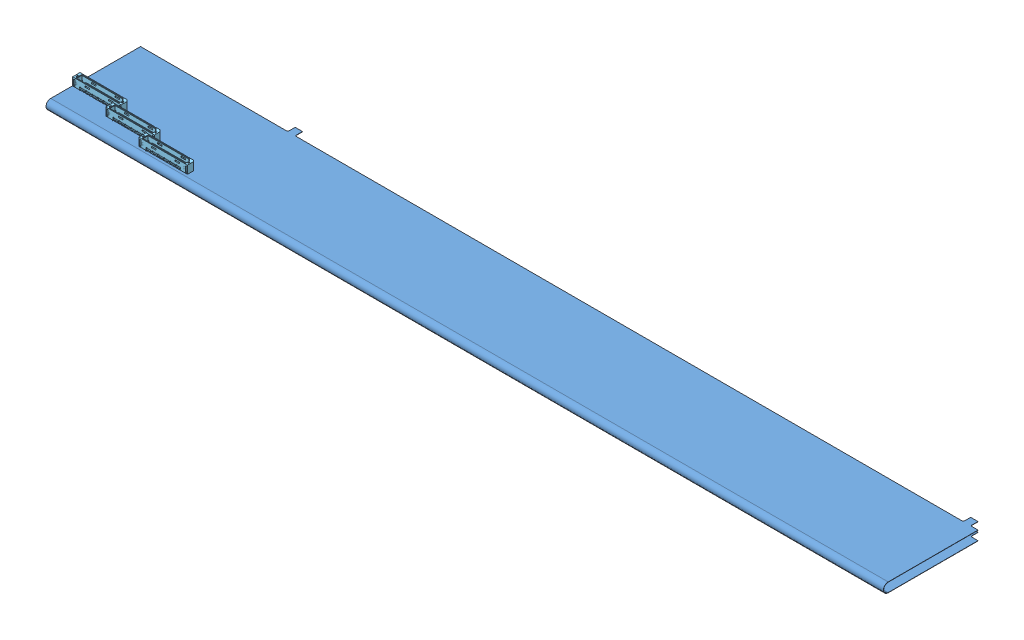
SolidWorks assembly IST Module rev 8_12 extruded, configuration Default. Lengths in mm.
Overall size (568.8 12.6 69.21).
53 component instances, 5 part files, 20 mates.
Components (placement in the parent):
- IST Kapton Hybrid rev 5_12 Extruded-1: IST Kapton Hybrid rev 5_12 Extruded [Default] at origin size (568.8 6.43 69.21)
- IST Silicon Sensor and APV assy rev 5_11-6: IST Silicon Sensor and APV assy rev 5_11 [Default] at (-38.65 -6.4251 21) x (1 0 0) z (0 0 -1) size (76.9 0.3 49.22)
  - IST Silicon Sensor rev1-2: IST Silicon Sensor rev1 [Default] x (-1 0 0) z (0 0 -1) size (76.9 0.3 40)
  - IST APV 25 Chip rev1-37: IST APV 25 Chip rev1 [Default] at (31.375 0 -25.119) x (0 0 1) z (-1 0 0) size (8.2 0.3 7.17)
  - IST APV 25 Chip rev1-2: IST APV 25 Chip rev1 [Default] at (18.825 0 -25.119) x (0 0 1) z (-1 0 0) size (8.2 0.3 7.17)
  - IST APV 25 Chip rev1-3: IST APV 25 Chip rev1 [Default] at (6.275 0 -25.119) x (0 0 1) z (-1 0 0) size (8.2 0.3 7.17)
  - IST APV 25 Chip rev1-4: IST APV 25 Chip rev1 [Default] at (-6.275 0 -25.119) x (0 0 1) z (-1 0 0) size (8.2 0.3 7.17)
  - IST APV 25 Chip rev1-5: IST APV 25 Chip rev1 [Default] at (-18.825 0 -25.119) x (0 0 1) z (-1 0 0) size (8.2 0.3 7.17)
  - IST APV 25 Chip rev1-6: IST APV 25 Chip rev1 [Default] at (-31.375 0 -25.119) x (0 0 1) z (-1 0 0) size (8.2 0.3 7.17)
- IST Silicon Sensor and APV assy rev 5_11-2: IST Silicon Sensor and APV assy rev 5_11 [Default] at (-115.95 -6.4251 21) x (1 0 0) z (0 0 -1) size (76.9 0.3 49.22)
  - IST Silicon Sensor rev1-2: IST Silicon Sensor rev1 [Default] x (-1 0 0) z (0 0 -1) size (76.9 0.3 40)
  - IST APV 25 Chip rev1-37: IST APV 25 Chip rev1 [Default] at (31.375 0 -25.119) x (0 0 1) z (-1 0 0) size (8.2 0.3 7.17)
  - IST APV 25 Chip rev1-2: IST APV 25 Chip rev1 [Default] at (18.825 0 -25.119) x (0 0 1) z (-1 0 0) size (8.2 0.3 7.17)
  - IST APV 25 Chip rev1-3: IST APV 25 Chip rev1 [Default] at (6.275 0 -25.119) x (0 0 1) z (-1 0 0) size (8.2 0.3 7.17)
  - IST APV 25 Chip rev1-4: IST APV 25 Chip rev1 [Default] at (-6.275 0 -25.119) x (0 0 1) z (-1 0 0) size (8.2 0.3 7.17)
  - IST APV 25 Chip rev1-5: IST APV 25 Chip rev1 [Default] at (-18.825 0 -25.119) x (0 0 1) z (-1 0 0) size (8.2 0.3 7.17)
  - IST APV 25 Chip rev1-6: IST APV 25 Chip rev1 [Default] at (-31.375 0 -25.119) x (0 0 1) z (-1 0 0) size (8.2 0.3 7.17)
- IST Silicon Sensor and APV assy rev 5_11-3: IST Silicon Sensor and APV assy rev 5_11 [Default] at (-193.25 -6.4251 21) x (1 0 0) z (0 0 -1) size (76.9 0.3 49.22)
  - IST Silicon Sensor rev1-2: IST Silicon Sensor rev1 [Default] x (-1 0 0) z (0 0 -1) size (76.9 0.3 40)
  - IST APV 25 Chip rev1-37: IST APV 25 Chip rev1 [Default] at (31.375 0 -25.119) x (0 0 1) z (-1 0 0) size (8.2 0.3 7.17)
  - IST APV 25 Chip rev1-2: IST APV 25 Chip rev1 [Default] at (18.825 0 -25.119) x (0 0 1) z (-1 0 0) size (8.2 0.3 7.17)
  - IST APV 25 Chip rev1-3: IST APV 25 Chip rev1 [Default] at (6.275 0 -25.119) x (0 0 1) z (-1 0 0) size (8.2 0.3 7.17)
  - IST APV 25 Chip rev1-4: IST APV 25 Chip rev1 [Default] at (-6.275 0 -25.119) x (0 0 1) z (-1 0 0) size (8.2 0.3 7.17)
  - IST APV 25 Chip rev1-5: IST APV 25 Chip rev1 [Default] at (-18.825 0 -25.119) x (0 0 1) z (-1 0 0) size (8.2 0.3 7.17)
  - IST APV 25 Chip rev1-6: IST APV 25 Chip rev1 [Default] at (-31.375 0 -25.119) x (0 0 1) z (-1 0 0) size (8.2 0.3 7.17)
- IST Silicon Sensor and APV assy rev 5_11-4: IST Silicon Sensor and APV assy rev 5_11 [Default] at (-270.55 -6.4251 21) x (1 0 0) z (0 0 -1) size (76.9 0.3 49.22)
  - IST Silicon Sensor rev1-2: IST Silicon Sensor rev1 [Default] x (-1 0 0) z (0 0 -1) size (76.9 0.3 40)
  - IST APV 25 Chip rev1-37: IST APV 25 Chip rev1 [Default] at (31.375 0 -25.119) x (0 0 1) z (-1 0 0) size (8.2 0.3 7.17)
  - IST APV 25 Chip rev1-2: IST APV 25 Chip rev1 [Default] at (18.825 0 -25.119) x (0 0 1) z (-1 0 0) size (8.2 0.3 7.17)
  - IST APV 25 Chip rev1-3: IST APV 25 Chip rev1 [Default] at (6.275 0 -25.119) x (0 0 1) z (-1 0 0) size (8.2 0.3 7.17)
  - IST APV 25 Chip rev1-4: IST APV 25 Chip rev1 [Default] at (-6.275 0 -25.119) x (0 0 1) z (-1 0 0) size (8.2 0.3 7.17)
  - IST APV 25 Chip rev1-5: IST APV 25 Chip rev1 [Default] at (-18.825 0 -25.119) x (0 0 1) z (-1 0 0) size (8.2 0.3 7.17)
  - IST APV 25 Chip rev1-6: IST APV 25 Chip rev1 [Default] at (-31.375 0 -25.119) x (0 0 1) z (-1 0 0) size (8.2 0.3 7.17)
- IST Silicon Sensor and APV assy rev 5_11-5: IST Silicon Sensor and APV assy rev 5_11 [Default] at (-347.85 -6.4251 21) x (1 0 0) z (0 0 -1) size (76.9 0.3 49.22)
  - IST Silicon Sensor rev1-2: IST Silicon Sensor rev1 [Default] x (-1 0 0) z (0 0 -1) size (76.9 0.3 40)
  - IST APV 25 Chip rev1-37: IST APV 25 Chip rev1 [Default] at (31.375 0 -25.119) x (0 0 1) z (-1 0 0) size (8.2 0.3 7.17)
  - IST APV 25 Chip rev1-2: IST APV 25 Chip rev1 [Default] at (18.825 0 -25.119) x (0 0 1) z (-1 0 0) size (8.2 0.3 7.17)
  - IST APV 25 Chip rev1-3: IST APV 25 Chip rev1 [Default] at (6.275 0 -25.119) x (0 0 1) z (-1 0 0) size (8.2 0.3 7.17)
  - IST APV 25 Chip rev1-4: IST APV 25 Chip rev1 [Default] at (-6.275 0 -25.119) x (0 0 1) z (-1 0 0) size (8.2 0.3 7.17)
  - IST APV 25 Chip rev1-5: IST APV 25 Chip rev1 [Default] at (-18.825 0 -25.119) x (0 0 1) z (-1 0 0) size (8.2 0.3 7.17)
  - IST APV 25 Chip rev1-6: IST APV 25 Chip rev1 [Default] at (-31.375 0 -25.119) x (0 0 1) z (-1 0 0) size (8.2 0.3 7.17)
- IST Silicon Sensor and APV assy rev 5_11-7: IST Silicon Sensor and APV assy rev 5_11 [Default] at (-425.15 -6.4251 21) x (1 0 0) z (0 0 -1) size (76.9 0.3 49.22)
  - IST Silicon Sensor rev1-2: IST Silicon Sensor rev1 [Default] x (-1 0 0) z (0 0 -1) size (76.9 0.3 40)
  - IST APV 25 Chip rev1-37: IST APV 25 Chip rev1 [Default] at (31.375 0 -25.119) x (0 0 1) z (-1 0 0) size (8.2 0.3 7.17)
  - IST APV 25 Chip rev1-2: IST APV 25 Chip rev1 [Default] at (18.825 0 -25.119) x (0 0 1) z (-1 0 0) size (8.2 0.3 7.17)
  - IST APV 25 Chip rev1-3: IST APV 25 Chip rev1 [Default] at (6.275 0 -25.119) x (0 0 1) z (-1 0 0) size (8.2 0.3 7.17)
  - IST APV 25 Chip rev1-4: IST APV 25 Chip rev1 [Default] at (-6.275 0 -25.119) x (0 0 1) z (-1 0 0) size (8.2 0.3 7.17)
  - IST APV 25 Chip rev1-5: IST APV 25 Chip rev1 [Default] at (-18.825 0 -25.119) x (0 0 1) z (-1 0 0) size (8.2 0.3 7.17)
  - IST APV 25 Chip rev1-6: IST APV 25 Chip rev1 [Default] at (-31.375 0 -25.119) x (0 0 1) z (-1 0 0) size (8.2 0.3 7.17)
- IST Thermal sensor-1: IST Thermal sensor [Default] at (-370.2525 -7.0251 57.6065) size (1.62 0.6 1.62)
- IST Readout Board Connector Female-2: IST Readout Board Connector Female [Default] at (-489.0005 1.3031 56.918) size (33 6.43 5.25)
- IST Readout Board Connector Female-3: IST Readout Board Connector Female [Default] at (-518.0005 1.3031 50.418) size (33 6.43 5.25)
- IST Readout Board Connector Female-4: IST Readout Board Connector Female [Default] at (-547.0005 1.3031 43.918) size (33 6.43 5.25)
Mates (geometry in assembly coordinates):
- Coincident1: coincident anti-aligned: plane of IST Kapton Hybrid rev 5_12 Extruded-1 through (5 -6.4251 0) normal (0 -1 0); plane of IST Silicon Sensor and APV assy rev 5_11-6/IST Silicon Sensor rev1-2 through (-77.1 -6.4251 41) normal (0 1 0)
- Distance1: distance = 1 mm aligned: plane of IST Silicon Sensor and APV assy rev 5_11-6/IST Silicon Sensor rev1-2 through (-0.2 -6.7251 1) normal (0 0 -1); plane of IST Kapton Hybrid rev 5_12 Extruded-1 through (5 -6.4251 0) normal (0 0 -1)
- Distance2: distance = 5.2 mm aligned: plane of IST Silicon Sensor and APV assy rev 5_11-6/IST Silicon Sensor rev1-2 through (-0.2 -6.7251 1) normal (1 0 0); plane of IST Kapton Hybrid rev 5_12 Extruded-1 through (5 -3.2126 61) normal (1 0 0)
- Coincident17: coincident anti-aligned: plane of IST Kapton Hybrid rev 5_12 Extruded-1 through (5 -6.4251 0) normal (0 -1 0); plane of IST Thermal sensor-1 through (-369.44 -6.4251 56.794) normal (0 1 0)
- Parallel2: parallel aligned: plane of IST Silicon Sensor and APV assy rev 5_11-7/IST Silicon Sensor rev1-2 through (-386.7 -6.7251 41) normal (0 0 1); plane of IST Thermal sensor-1 through (-371.065 -6.4251 58.419) normal (0 0 1)
- Parallel6: parallel aligned: plane of assembly through (0 0 0) normal (0 0 1); plane of IST Readout Board Connector Female-2 through (-489.0005 1.3031 56.918) normal (0 0 1)
- Distance28: distance = 192.735 mm aligned: plane of IST Thermal sensor-1 through (-371.065 -6.4251 58.419) normal (-1 0 0); plane of IST Kapton Hybrid rev 5_12 Extruded-1 through (-563.8 -3.2126 61) normal (-1 0 0)
- Distance29: distance = 56.794 mm aligned: plane of IST Thermal sensor-1 through (-371.065 -6.4251 56.794) normal (0 0 -1); plane of IST Kapton Hybrid rev 5_12 Extruded-1 through (-6 -6.4251 0) normal (0 0 -1)
- Coincident43: coincident aligned: axis of IST Kapton Hybrid rev 5_12 Extruded-1 through (-502.001 -0.2311 56.918) axis (0 1 0); axis of IST Readout Board Connector Female-2 through (-502.001 -0.5428 56.918) axis (0 1 0)
- Coincident44: coincident anti-aligned: plane of IST Kapton Hybrid rev 5_12 Extruded-1 through (5 0 0) normal (0 1 0); plane of ? through (-500.474 0 54.1674) normal (0 -1 0)
- Coincident47: coincident anti-aligned: plane of IST Kapton Hybrid rev 5_12 Extruded-1 through (5 0 0) normal (0 1 0); plane of ? through (-500.728 0 59.6686) normal (0 -1 0)
- Coincident48: coincident aligned: axis of IST Kapton Hybrid rev 5_12 Extruded-1 through (-502.001 -0.2311 56.918) axis (0 1 0); axis of IST Readout Board Connector Female-2 through (-502.001 -0.5428 56.918) axis (0 1 0)
- Coincident49: coincident anti-aligned: plane of IST Kapton Hybrid rev 5_12 Extruded-1 through (5 0 0) normal (0 1 0); plane of IST Readout Board Connector Female-2 through (-500.728 0 59.6686) normal (0 -1 0)
- Parallel7: parallel aligned: plane of IST Kapton Hybrid rev 5_12 Extruded-1 through (-464.8 -6.4251 0) normal (0 0 -1); plane of IST Readout Board Connector Female-2 through (-473.5006 0.2032 54.418) normal (0 0 -1)
- Coincident50: coincident aligned: axis of IST Kapton Hybrid rev 5_12 Extruded-1 through (-531.001 -0.2311 50.418) axis (0 1 0); axis of IST Readout Board Connector Female-3 through (-531.001 -0.5428 50.418) axis (0 1 0)
- Coincident51: coincident anti-aligned: plane of IST Kapton Hybrid rev 5_12 Extruded-1 through (5 0 0) normal (0 1 0); plane of IST Readout Board Connector Female-3 through (-529.728 0 53.1686) normal (0 -1 0)
- Parallel8: parallel aligned: plane of IST Readout Board Connector Female-2 through (-473.5006 0.2032 54.418) normal (0 0 -1); plane of IST Readout Board Connector Female-3 through (-502.5006 0.2032 47.918) normal (0 0 -1)
- Coincident53: coincident aligned: axis of IST Kapton Hybrid rev 5_12 Extruded-1 through (-560.001 -0.2311 43.918) axis (0 1 0); axis of IST Readout Board Connector Female-4 through (-560.001 -0.5428 43.918) axis (0 1 0)
- Coincident54: coincident anti-aligned: plane of IST Kapton Hybrid rev 5_12 Extruded-1 through (5 0 0) normal (0 1 0); plane of IST Readout Board Connector Female-4 through (-558.728 0 46.6686) normal (0 -1 0)
- Parallel9: parallel aligned: plane of IST Readout Board Connector Female-3 through (-502.5006 0.2032 47.918) normal (0 0 -1); plane of IST Readout Board Connector Female-4 through (-531.5006 0.2032 41.418) normal (0 0 -1)
